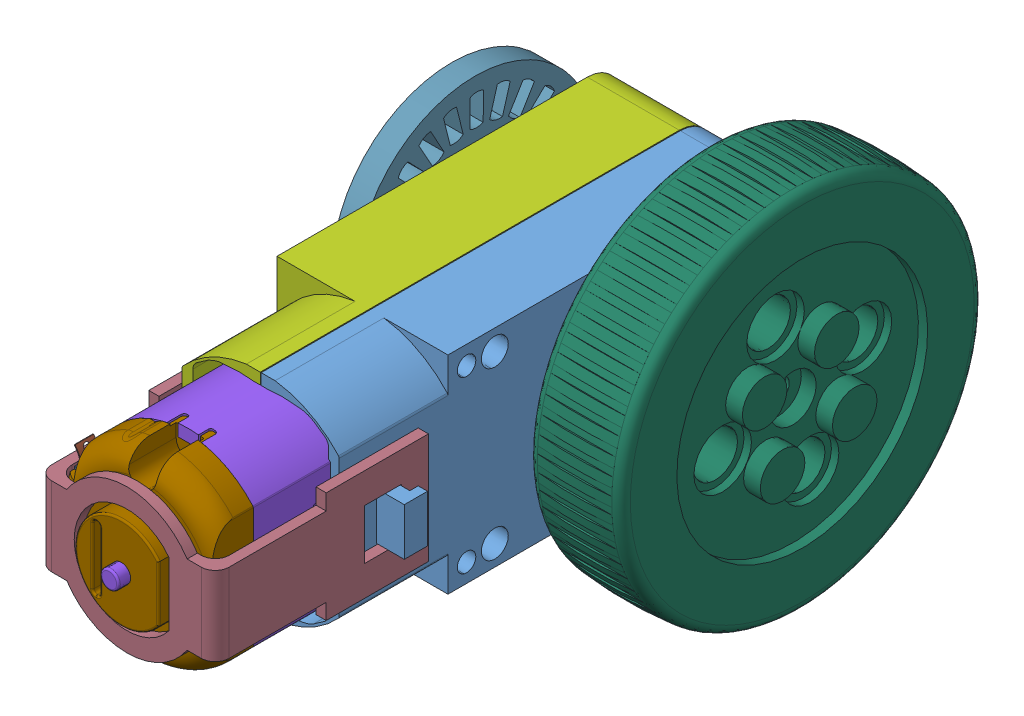
SolidWorks assembly Motor, configuration 默认. Lengths in mm.
Overall size (39.53 54.08 80.8).
19 component instances, 16 part files, 7 mates.
Components (placement in the parent):
- MoterDeviceNew-1: MoterDeviceNew [默认] at (-6.9491 7.5604 0) (suppressed, hidden)
- MotorReductorYellow_Eng-2: MotorReductorYellow_Eng [Default] at (4.5509 20.7104 2.7356) x (0 -1 0) z (-1 0 0) size (35.43 71.48 35.6)
  - MotorReductorYellow_Eng06-1: MotorReductorYellow_Eng06 [Default] at origin size (22.3 53.9 19.6)
  - MotorReductorYellow_Eng04-1: MotorReductorYellow_Eng04 [Default] at (0 4.45 6.6) x (0.525355 0.850883 0) z (0 0 -1) size (14 14 7.3)
  - MotorReductorYellow_Eng02-1: MotorReductorYellow_Eng02 [Default] at (0 4.45 14) x (-0.99474 -0.102429 0) z (0 0 -1) size (16.9 16.9 5.4)
  - MotorReductorYellow_Eng03-1: MotorReductorYellow_Eng03 [Default] at (0 -7.2 10.5) x (0.110699 0.993854 0) z (0 0 -1) size (18.8 18.8 5.6)
  - MotorReductorYellow_Eng01-1: MotorReductorYellow_Eng01 [Default] at (0 -7.2 14.5) x (0.515467 -0.856909 0) z (0 0 1) size (18.38 18.36 13.8)
  - MotorReductorYellow_Eng07-1: MotorReductorYellow_Eng07 [Default] at (0 -7.2 5.5) x (-0.515467 0.856909 0) z (0 0 -1) size (5.45 5.45 12.2)
  - MotorReductorYellow_Eng05-1: MotorReductorYellow_Eng05 [Default] at (0 0 19.9) x (-1 0 0) z (0 0 -1) size (22.3 53.9 12.3)
  - MotorReductorYellow-1: MotorReductorYellow [Default] at (0 28.5 9.9) x (1 0 0) z (0 -1 0) size (19.85 16.19 38.5)
    - MotorReductorYellow01-1: MotorReductorYellow01 [Default] at origin size (19.8 15.08 38.5)
    - MotorReductorYellow02-1: MotorReductorYellow02 [Default] at (0 0 -9.3539) size (19.85 16.1 11.4)
    - Part4^MotorReductorYellow-1: Part4^MotorReductorYellow [Default] at (0 0 -13.3161) size (7.95 1.2 3.32) (virtual)
    - MotorReductorYellow04-1: MotorReductorYellow04 [Default] at (0 0 -13.3161) size (12.07 11.04 24.42)
    - MotorReductorYellow03-1: MotorReductorYellow03 [Default] at (0 0 20.4408) size (5 5 7) (hidden)
  - MotorReductorYellow03-1: MotorReductorYellow03 [Default] at (0 8.5592 9.9) x (-0.661402 0 0.750031) z (0 -1 0) size (5 5 7)
  - MotorReductorYellow_Eng08-2: MotorReductorYellow_Eng08 [Default] at (0 44.65 9.9) x (1 0 0) z (0 -1 0) size (15.49 19.1 22.95)
  - wheel black-1: wheel black [Default] at (0 -7.2 24.28) x (0.515467 -0.856909 0) z (-0.856909 -0.515467 0) size (25.82 3.52 25.82)
- RouePourimpression-2: RouePourimpression [Défaut] at (5.4809 20.7104 -4.4644) x (0 0.856909 -0.515467) z (1 0 0) size (39.41 39.4 10.8)
Mates (geometry in assembly coordinates):
- 重合1: coincident anti-aligned: plane of MoterDeviceNew-1 through (-6.9491 9.5604 0) normal (0 1 0); plane of MotorReductorYellow_Eng-2/MotorReductorYellow_Eng05-1 through (-14.3491 9.5604 2.7356) normal (0 -1 0)
- 平行1: parallel aligned: plane of MoterDeviceNew-1 through (5.4809 9.5604 -20.84) normal (0 0 -1); plane of MotorReductorYellow_Eng-2/MotorReductorYellow_Eng06-1 through (3.5509 20.7104 -15.7644) normal (0 0 -1)
- 重合3: coincident anti-aligned: plane of MoterDeviceNew-1 through (3.0509 31.5604 18.42) normal (-1 0 0); plane of MotorReductorYellow_Eng-2/MotorReductorYellow_Eng06-1 through (3.0509 13.2269 32.9356) normal (1 0 0)
- 重合4: coincident anti-aligned: plane of MoterDeviceNew-1 through (-0.4436 23.5904 -15.7644) normal (0 0 1); plane of MotorReductorYellow_Eng-2/MotorReductorYellow_Eng06-1 through (3.5509 20.7104 -15.7644) normal (0 0 -1)
- 平行5: parallel anti-aligned: plane of MotorReductorYellow_Eng-2/MotorReductorYellow_Eng07-1 through (4.4009 21.1982 -7.1454) normal (0 0.856909 -0.515467); plane of RouePourimpression-2 through (12.4809 23.6312 -3.7798) normal (0 -0.856909 0.515467)
- 重合15: coincident anti-aligned: plane of MoterDeviceNew-1 through (5.4809 9.5604 20.84) normal (1 0 0); plane of RouePourimpression-2 through (5.4809 20.7104 -4.4644) normal (-1 0 0)
- 同心3: concentric aligned: circle of MotorReductorYellow_Eng-2/MotorReductorYellow_Eng07-1; circle of RouePourimpression-2
